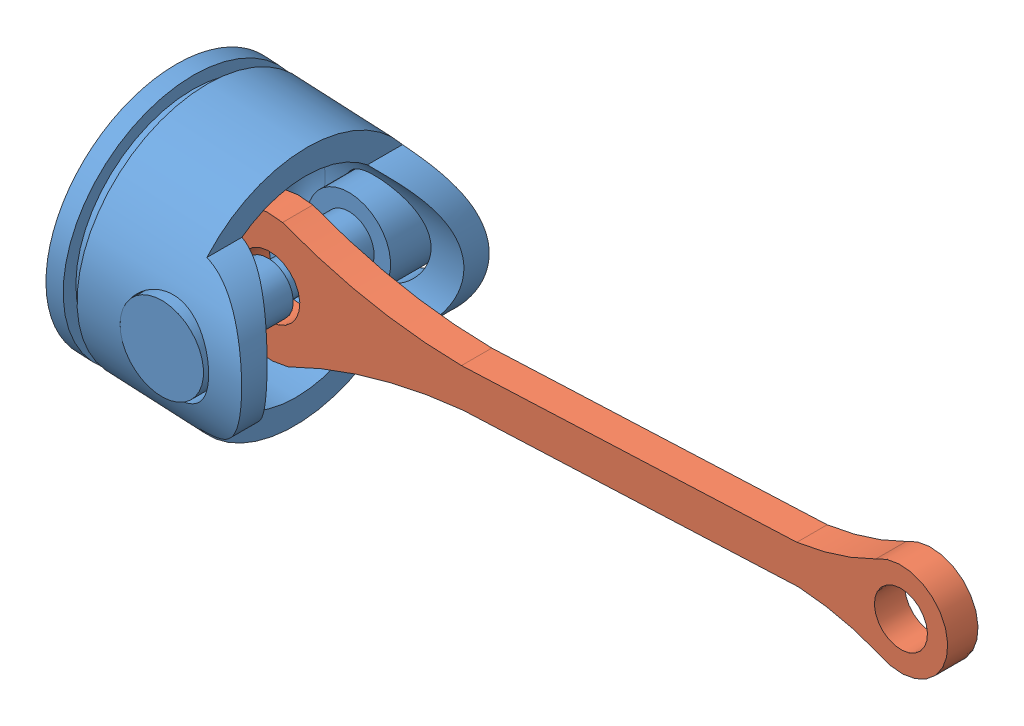
SolidWorks assembly piston connecting rod 1, configuration Default. Lengths in mm.
Overall size (326.44 102.2 98).
2 component instances, 2 part files, 1 mates.
Components (placement in the parent):
- piston-2: piston [Default] at (-86.789 -24.8229 -129.3791) x (0.05016 0.998741 0) z (0 0 1) size (98 86.21 98)
- rod-2: rod [Default] at (-31.0215 -19.4267 -134.9647) x (0.999044 0.043707 0) z (0 0 1) size (293.5 50 12)
Mates (geometry in assembly coordinates):
- Concentric1: concentric aligned: circle of piston-2; circle of rod-2
